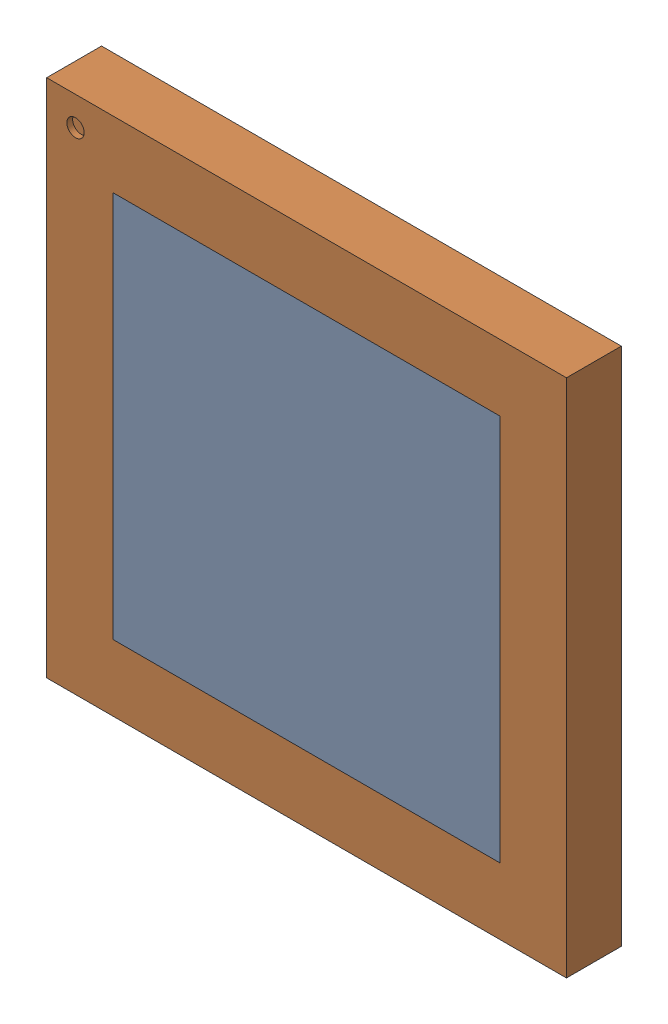
SolidWorks assembly 220046-MICRON MT9V022177ATC, configuration Default. Lengths in mm.
Overall size (9 9 1.25).
2 component instances, 2 part files, 0 mates.
Components (placement in the parent):
- MT9V022 WINDOW-1: MT9V022 WINDOW [Default] at (0 0 0.55) size (6.7 6.7 0.4)
- MT9V022 PACKAGE-1: MT9V022 PACKAGE [Default] at origin size (9 9 1.25)
